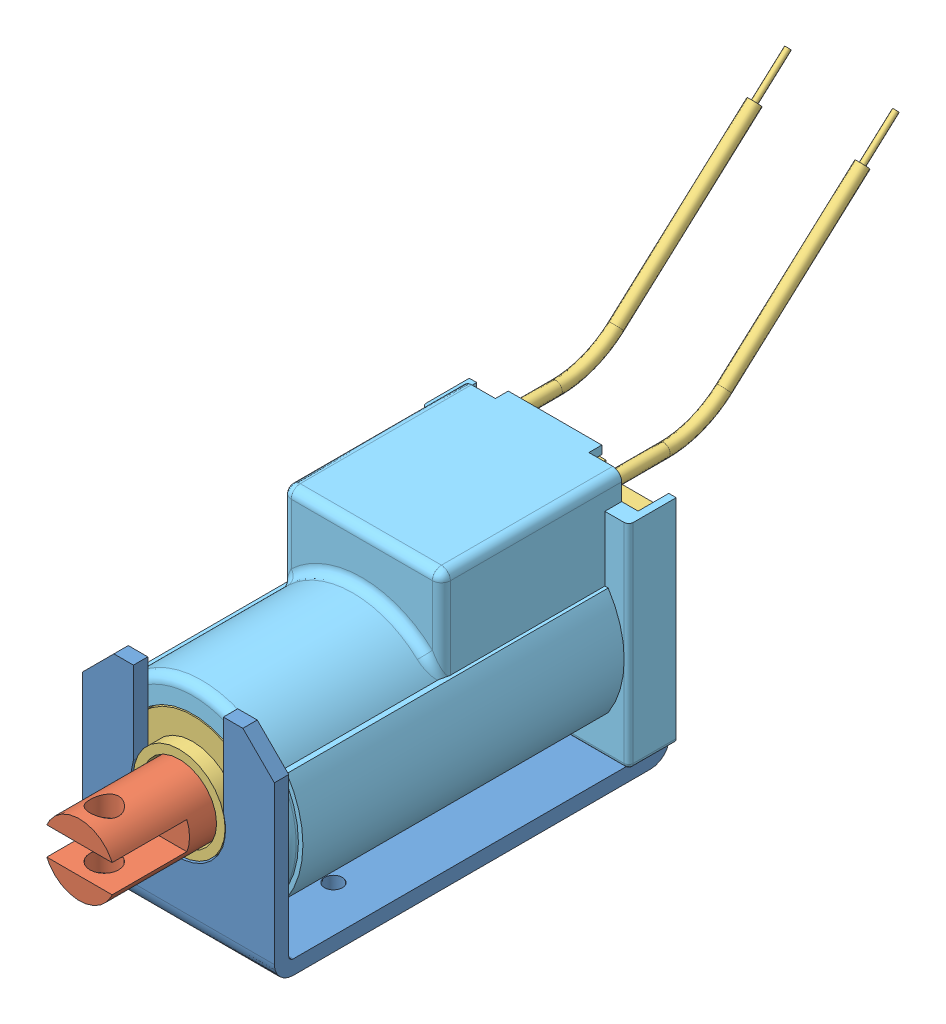
SolidWorks assembly DSOL-0844 - SOLENOID, OPEN FRAME, PULL, CONTINOUS, .500 STROKE, 12VDC, configuration Rotated 90 - Retracted (Power On). Lengths in mm.
Overall size (23 45.36 84.99).
5 component instances, 5 part files, 4 mates.
Components (placement in the parent):
- FRAME_╣w│]-1: FRAME_╣w│] [Default] at (-10.67 0 -20.37) x (0 0 -1) z (1 0 0)
- plunger update_╣w│]-1: plunger update_╣w│] [Default] at (0 0 -9.595) x (0 0 1) z (1 0 0)
- BOBBIN_╣w│]-1: BOBBIN_╣w│] [Default] at (0 1.15 -39.52)
- stopper SUM24L_╣w│]-1: stopper SUM24L_╣w│] [Default] at (0 0 -16.3126) x (0.817656 -0.575707 0) z (0.575707 0.817656 0)
- case cover_╣w│]-1: case cover_╣w│] [Default] at origin
Mates (geometry in assembly coordinates):
- Concentric1: concentric anti-aligned: cylinder of plunger update_╣w│]-1 through (0 0 -39.1356) axis (0 0 -1) radius 3.95; cylinder of case cover_╣w│]-1 through (0 0 -37.47) axis (0 0 1) radius 11
- Distance1: distance = 11 mm aligned: plane of plunger update_╣w│]-1 through (0 -3.95 12.6) normal (0 0 1); plane of FRAME_╣w│]-1 through (10.67 10.75 1.6) normal (0 0 1)
- Parallel1: parallel aligned: plane of plunger update_╣w│]-1 through (-1.55 4.9491 4.3) normal (1 0 0); plane of assembly through (0 0 0) normal (1 0 0)
- Parallel2: parallel anti-aligned: plane of plunger update_╣w│]-1 through (4.9491 1.55 4.3) normal (0 -1 0); plane of assembly through (0 0 0) normal (0 1 0)
